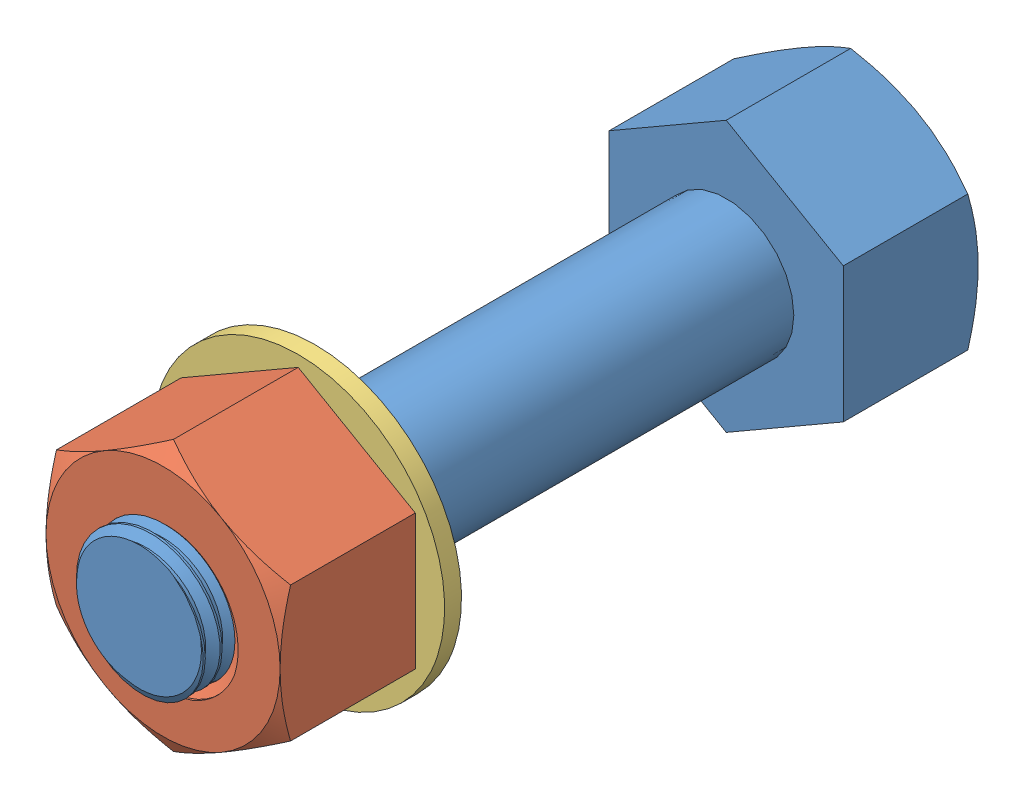
SolidWorks assembly Assem1, configuration Default. Lengths in mm.
Overall size (67.47 67.47 130.19).
3 component instances, 3 part files, 6 mates.
Components (placement in the parent):
- BOLT-1: BOLT [Default] at (25.373 73.0261 43.6393) size (41.57 48 130.19)
- NUT-1: NUT [Default] at (25.373 73.0261 143.6393) x (-0.5 0.866025 0) z (0.866025 0.5 0) size (41.57 26.18 48)
- WASHER-2: WASHER [Default] at (25.373 73.0261 140.6393) x (0.930067 -0.367389 0) z (0 0 1) size (52 52 3)
Mates (geometry in assembly coordinates):
- Concentric5: concentric aligned: cylinder of BOLT-1 through (25.373 73.0261 172.6393) axis (0 0 -1) radius 12; cylinder of WASHER-2 through (25.373 73.0261 143.6393) axis (0 0 -1) radius 26
- Concentric6: concentric anti-aligned: cylinder of BOLT-1 through (25.373 73.0261 172.6393) axis (0 0 -1) radius 12; circle of WASHER-2
- Concentric8: concentric: cylinder of BOLT-1 through (25.373 73.0261 172.6393) axis (0 0 -1) radius 12; circle of NUT-1
- Distance3: distance = 100 mm: plane of BOLT-1 through (25.373 73.0261 67.6393) normal (0 0 1); plane of NUT-1 through (25.373 73.0261 167.6393) normal (0 0 1)
- Parallel3: parallel: plane of BOLT-1 through (46.1576 61.0261 67.6393) normal (1 0 0); plane of NUT-1 through (46.1576 61.0261 167.6393) normal (1 0 0)
- Coincident6: coincident: plane of NUT-1 through (25.373 73.0261 143.6393) normal (0 0 -1); plane of WASHER-2 through (25.373 73.0261 143.6393) normal (0 0 1)
